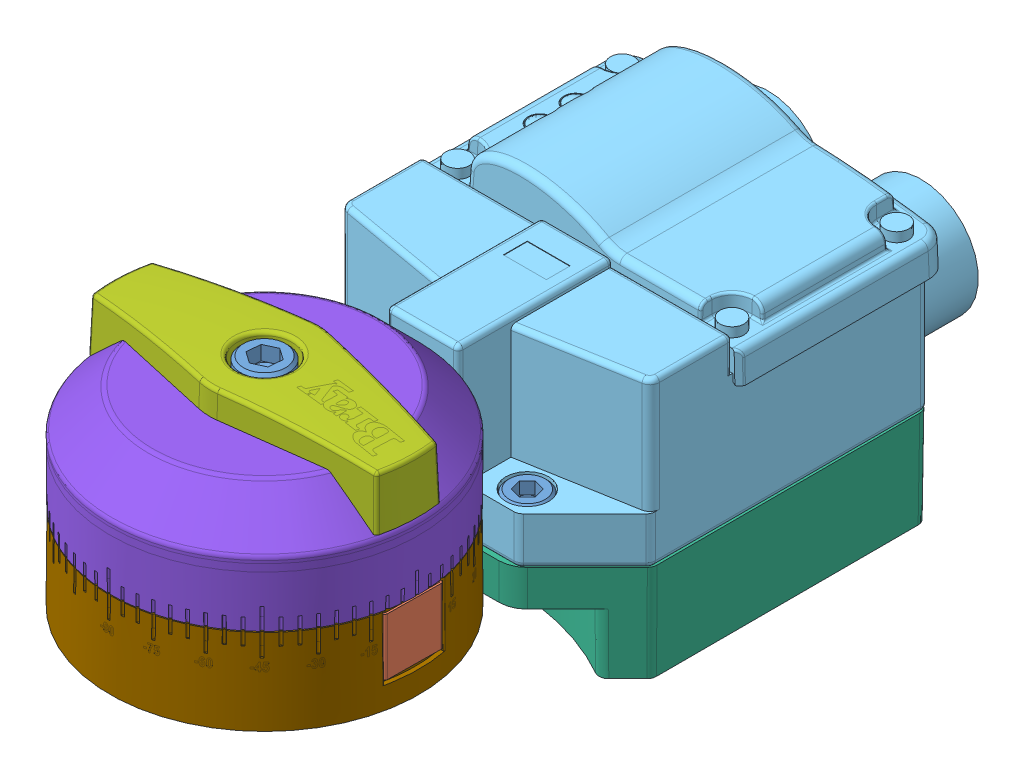
SolidWorks assembly Assem3, configuration Default. Lengths in mm.
Overall size (68 72.61 154.29).
13 component instances, 9 part files, 20 mates.
Components (placement in the parent):
- socket head cap screw_am-1: socket head cap screw_am [B18.3.1M - 5 x 0.8 x 12 Hex SHCS -- 12NHX] at (-512.7656 91.002 -480.46) x (0 -1 0) z (-0.706848 0 -0.707366) size (17 8.5 8.5)
- socket head cap screw_am-2: socket head cap screw_am [B18.3.1M - 6 x 1.0 x 30 Hex SHCS -- 30NHX] at (-527.7781 127.7182 -440.4327) x (0 -1 0) z (-0.995947 0 -0.089939) size (36 10 10)
- 54-000A-73500-1: 54-000A-73500 [Default] at (-527.4972 106.2477 -472.6265) x (-1 -0.000194 0.00096) z (-0.000958 -0.008727 -0.999961) size (12.19 11.94 6.35)
- 07-5623-72107-1: 07-5623-72107 [Default] at (-512.7895 77.9337 -505.46) x (0 -1 0) z (0.643698 0 0.76528) size (25 9.12 9.2)
- socket head cap screw_am-3: socket head cap screw_am [B18.3.1M - 5 x 0.8 x 12 Hex SHCS -- 12NHX] at (-542.7906 91.002 -480.46) x (0 -1 0) z (-0.706848 0 0.707366) size (17 8.5 8.5)
- 54-000A-73500-2: 54-000A-73500 [Default] at (-496.0806 93.6814 -440.0987) x (0.011705 0 -0.999931) z (0.999931 0 0.011705) size (12.19 11.94 6.35)
- 07-5623-72107-2: 07-5623-72107 [Default] at (-542.7667 77.9337 -505.46) x (0 -1 0) z (0.643698 0 -0.76528) size (25 9.12 9.2)
- 54-160A-705P0-1: 54-160A-705P0 [Default] at (-527.7781 109.8564 -440.4327) size (45.64 22.89 45.64)
- 54-0013-71104-1: 54-0013-71104 [Default] at (-527.7656 81.002 -506.96) size (68 40.45 88.5)
- 54-160A-705S0-1: 54-160A-705S0 [Default] at (-527.8297 81.002 -547.3746) x (-1 0 0.000958) z (-0.000958 0 -1) size (64.77 20.58 72.89)
- 54-000A-92512-1: 54-000A-92512 [Default] at (-527.7781 116.3842 -440.4327) x (-0.998952 0 -0.045767) z (0.045767 0 -0.998952) size (64.52 13.44 23.07)
- 54-000A-92511-1: 54-000A-92511 [Default] at (-527.7781 100.5092 -440.4327) x (-0.999932 0 -0.011665) z (0.011665 0 -0.999932) size (64.76 21.97 66.01)
- 54-000A-92510-1: 54-000A-92510 [Default] at (-527.7781 82.4244 -440.4327) x (0.011705 0 -0.999931) z (0.999931 0 0.011705) size (64.81 35.64 64.77)
Mates (geometry in assembly coordinates):
- Coincident1: coincident: plane of 54-160A-705P0-1 through (-527.7781 109.8564 -440.4327) normal (0 1 0); plane of 54-000A-92510-1 through (-527.5269 109.8564 -461.8942) normal (0 -1 0)
- Coincident2: coincident: plane of 54-000A-92511-1 through (-527.9249 113.0314 -427.8478) normal (0 -1 0); plane of 54-000A-92510-1 through (-527.628 113.0314 -453.2588) normal (0 1 0)
- Coincident3: coincident: plane of 54-000A-73500-2 through (-497.2792 99.6504 -446.2092) normal (-0.999931 0 -0.011705); plane of 54-000A-92510-1 through (-497.351 82.4244 -440.0765) normal (0.999931 0 0.011705)
- Parallel1: parallel: plane of 54-000A-73500-1 through (-521.4024 112.2177 -472.6844) normal (-0.000958 -0.008727 -0.999961); plane of 54-160A-705S0-1 through (-495.4447 81.002 -547.4056) normal (-0.000958 -0.008727 -0.999961)
- Coincident4: coincident: line of 54-000A-73500-1 through (-533.5924 108.4822 -471.3701) axis (-0.000203 0.999962 -0.008726); plane of 54-000A-92511-1 through (-533.5822 100.5092 -470.9316) normal (0.99973 0 -0.023239)
- Coincident5: coincident: plane of 54-0013-71104-1 through (-527.7656 81.002 -506.96) normal (0 -1 0); plane of 54-160A-705S0-1 through (-512.7656 81.002 -480.46) normal (0 1 0)
- Coincident6: coincident: plane of socket head cap screw_am-1 through (-515.7719 86.002 -477.4559) normal (0 -1 0); plane of 54-0013-71104-1 through (-512.7656 86.002 -480.46) normal (0 1 0)
- Parallel2: parallel: line of 54-000A-73500-2 through (-496.6853 87.7124 -434.0094) axis (0 1 0); plane of 54-000A-92510-1 through (-497.4231 82.4244 -433.9174) normal (0.046595 0 -0.998914)
- Coincident7: coincident: plane of socket head cap screw_am-2 through (-528.2278 121.7182 -435.4529) normal (0 -1 0); plane of 54-000A-92512-1 through (-528.0298 121.7182 -434.9384) normal (0 1 0)
- Concentric1: concentric: cylinder of 54-000A-92512-1 through (-527.7781 116.3842 -440.4327) axis (0 -1 0) radius 3.3; cylinder of 54-000A-92511-1 through (-527.7781 103.6976 -440.4327) axis (0 1 0) radius 3.3
- Distance1: distance = 0.1778 mm: plane of 54-000A-92511-1 through (-527.8951 116.2064 -430.4003) normal (0 1 0); plane of 54-000A-92512-1 through (-528.117 116.3842 -433.0363) normal (0 -1 0)
- Concentric2: concentric: cone of 07-5623-72107-1 through (-512.7895 80.1837 -505.46) axis (0 -1 0); cone of 54-160A-705S0-1 through (-512.7895 81.002 -505.46) axis (0 -1 0)
- Concentric3: concentric: cylinder of 07-5623-72107-1 through (-512.7895 77.1337 -505.46) axis (0 -1 0) radius 2.5; cylinder of 54-160A-705S0-1 through (-512.7895 81.002 -505.46) axis (0 1 0) radius 2.8067
- Concentric4: concentric: cylinder of 54-000A-92511-1 through (-527.7781 103.6976 -440.4327) axis (0 1 0) radius 3.3; cylinder of 54-000A-92510-1 through (-527.7781 73.0906 -440.4327) axis (0 1 0) radius 3.3
- Concentric5: concentric: circle of 07-5623-72107-1; circle of 54-160A-705S0-1
- Concentric6: concentric: circle of 07-5623-72107-1; circle of 54-160A-705S0-1
- Concentric7: concentric: cylinder of 54-160A-705P0-1 through (-527.7781 119.1902 -440.4327) axis (0 -1 0) radius 3.3; cylinder of 54-000A-92510-1 through (-527.7781 73.0906 -440.4327) axis (0 1 0) radius 3.3
- Concentric8: concentric: cylinder of socket head cap screw_am-1 through (-512.7656 122.752 -480.46) axis (0 1 0) radius 4.25; cylinder of 54-0013-71104-1 through (-512.7656 76.1817 -480.46) axis (0 1 0) radius 4.5
- Concentric9: concentric: cylinder of socket head cap screw_am-2 through (-527.7781 159.4682 -440.4327) axis (0 1 0) radius 3; cylinder of 54-000A-92511-1 through (-527.7781 103.6976 -440.4327) axis (0 1 0) radius 3.3
- Concentric10: concentric: cylinder of 54-0013-71104-1 through (-512.7656 76.1817 -480.46) axis (0 1 0) radius 2.7; circle of 54-160A-705S0-1
